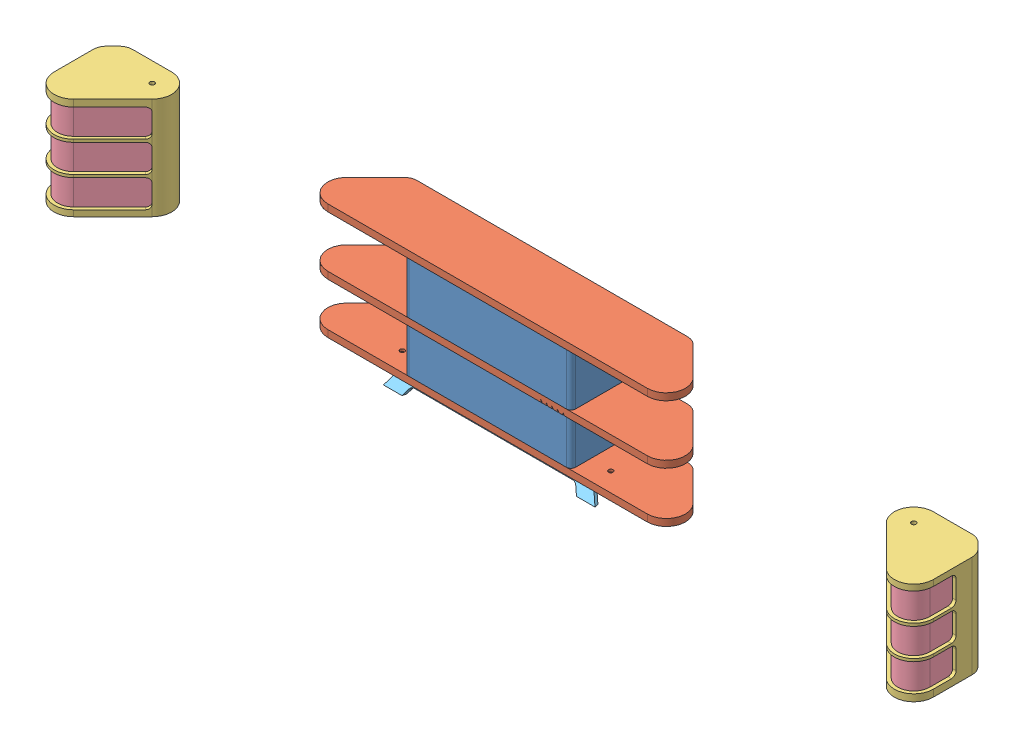
SolidWorks assembly Speakers removed, configuration Default. Lengths in mm.
Overall size (5109.88 725.08 617.93).
10 component instances, 5 part files, 25 mates.
Components (placement in the parent):
- Middle-1: Middle [Default] at (409.9999 227.4076 645.5134) size (914.4 558.8 355.6)
- top bottom-1: top bottom [Default] at (352.252 227.4076 660.7734) x (-1 0 0) z (0 0 1) size (1960.6 38.1 355.6)
- top bottom-2: top bottom [Default] at (467.7478 786.2076 660.7734) size (1960.6 38.1 355.6)
- speaker-1: speaker [Default] at (-1746.1738 107.9388 721.7134) x (0.707107 0 -0.707107) z (0.707107 0 0.707107) size (518.28 558.8 355.6)
- insert-1: insert [Default] at (-1800.5019 139.6888 633.9363) x (0.707107 0 -0.707107) z (0.707107 0 0.707107) size (480.18 508 317.5)
- speaker-2: speaker [Default] at (2566.1737 666.7388 721.7134) x (-0.707107 0 -0.707107) z (-0.707107 0 0.707107) size (518.28 558.8 355.6)
- insert-2: insert [Default] at (2653.9508 139.6888 667.3853) x (0.707107 0 0.707107) z (-0.707107 0 0.707107) size (480.18 508 317.5)
- top bottom-3: top bottom [Default] at (467.7478 466.011 660.7734) size (1960.6 38.1 355.6)
- feet-1: feet [Default] at (409.9999 198.1951 531.0014) x (1 0 0) z (0 -0.457029 0.889452) size (1159.95 101.27 19.05)
- feet-2: feet [Default] at (409.9999 198.1951 767.9726) x (-1 0 0) z (0 -0.457029 -0.889452) size (1159.95 101.27 19.05)
Mates (geometry in assembly coordinates):
- Coincident1: coincident anti-aligned: plane of Middle-1 through (409.9999 786.2076 645.5134) normal (0 1 0); plane of top bottom-2 through (-331.4645 786.2076 541.3734) normal (0 -1 0)
- Coincident2: coincident aligned: plane of Middle-1 through (-47.2001 786.2076 823.3134) normal (0 0 1); plane of top bottom-2 through (1280.027 824.3076 823.3134) normal (0 0 1)
- Coincident3: coincident aligned: plane of Middle-1 through (-47.2001 786.2076 823.3134) normal (0 0 1); plane of top bottom-1 through (-460.0272 189.3076 823.3134) normal (0 0 1)
- Coincident4: coincident anti-aligned: plane of Middle-1 through (409.9999 227.4076 645.5134) normal (0 -1 0); plane of top bottom-1 through (1151.4644 227.4076 541.3734) normal (0 1 0)
- Coincident5: coincident aligned: plane of top bottom-1 through (1355.4612 189.3076 641.1993) normal (0.707107 0 -0.707107); plane of top bottom-2 through (1359.7972 824.3076 645.5353) normal (0.707107 0 -0.707107)
- Width1: width anti-aligned: plane of top bottom-2 through (1359.7972 824.3076 645.5353) normal (0.707107 0 -0.707107); plane of top bottom-2 through (-535.4613 824.3076 641.1993) normal (-0.707107 0 -0.707107); plane of Middle-1 through (-47.2001 786.2076 823.3134) normal (-1 0 0); plane of Middle-1 through (867.1999 786.2076 823.3134) normal (1 0 0)
- Coincident7: coincident anti-aligned: plane of speaker-1 through (-765.667 107.9388 438.524) normal (-0.707107 0 -0.707107); plane of insert-1 through (-1179.114 647.6888 851.9709) normal (0.707107 0 0.707107)
- Coincident8: coincident anti-aligned: plane of speaker-1 through (-1093.7577 647.6888 721.7134) normal (0 -1 0); plane of insert-1 through (-1239.247 647.6888 543.9134) normal (0 1 0)
- Coincident9: coincident anti-aligned: plane of speaker-1 through (-1328.7077 666.7388 467.7134) normal (1 0 0); plane of insert-1 through (-1328.7077 647.6888 576.2242) normal (-1 0 0)
- Coincident11: coincident anti-aligned: plane of speaker-2 through (2238.083 666.7388 438.524) normal (0.707107 0 -0.707107); plane of insert-2 through (2435.9162 647.6888 636.3572) normal (-0.707107 0 0.707107)
- Coincident12: coincident anti-aligned: plane of speaker-2 through (2566.1737 647.6888 721.7134) normal (0 -1 0); plane of insert-2 through (2743.9737 647.6888 576.2242) normal (0 1 0)
- Coincident13: coincident anti-aligned: plane of speaker-2 through (2801.1237 107.9388 467.7134) normal (-1 0 0); plane of insert-2 through (2801.1237 647.6888 790.0072) normal (1 0 0)
- Coincident14: coincident aligned: plane of top bottom-2 through (1280.027 824.3076 823.3134) normal (0 0 1); plane of top bottom-3 through (1280.027 504.111 823.3134) normal (0 0 1)
- Coincident15: coincident aligned: plane of top bottom-2 through (-535.4613 824.3076 641.1993) normal (-0.707107 0 -0.707107); plane of top bottom-3 through (-535.4613 504.111 641.1993) normal (-0.707107 0 -0.707107)
- Coincident17: coincident anti-aligned: plane of top bottom-1 through (1151.4644 189.3076 541.3734) normal (0 -1 0); plane of feet-2 through (989.9752 189.3076 814.3493) normal (0 1 0)
- Coincident18: coincident anti-aligned: plane of top bottom-1 through (1151.4644 189.3076 541.3734) normal (0 -1 0); plane of feet-1 through (-169.9754 189.3076 484.6248) normal (0 1 0)
- Parallel1: parallel: plane of top bottom-1 through (-460.0272 189.3076 823.3134) normal (0 0 1); line of feet-2 through (938.1929 189.3076 772.5393) axis (-1 0 0)
- Width2: width anti-aligned: plane of top bottom-1 through (1355.4612 189.3076 641.1993) normal (0.707107 0 -0.707107); plane of top bottom-1 through (-539.7974 189.3076 645.5353) normal (-0.707107 0 -0.707107); plane of feet-1 through (-120.1337 177.9796 542.0317) normal (-0.871403 0.436336 0.224204); plane of feet-1 through (940.1336 177.9796 542.0317) normal (0.871403 0.436336 0.224204)
- Width3: width aligned: plane of top bottom-1 through (-539.7974 189.3076 645.5353) normal (-0.707107 0 -0.707107); plane of top bottom-1 through (1355.4612 189.3076 641.1993) normal (0.707107 0 -0.707107); plane of feet-2 through (-120.1337 177.9796 756.9423) normal (-0.871403 0.436336 -0.224204); plane of feet-2 through (940.1336 177.9796 756.9423) normal (0.871403 0.436336 -0.224204)
- Coincident22: coincident aligned: plane of speaker-2 through (2566.1737 107.9388 721.7134) normal (0 -1 0); plane of feet-2 through (989.9752 107.9388 814.3493) normal (0 -1 0)
- Coincident23: coincident aligned: plane of speaker-1 through (-1093.7577 107.9388 721.7134) normal (0 -1 0); plane of feet-2 through (989.9752 107.9388 814.3493) normal (0 -1 0)
- Coincident24: coincident aligned: plane of Middle-1 through (-47.2001 786.2076 467.7134) normal (0 0 -1); plane of speaker-1 through (-839.7577 666.7388 467.7134) normal (0 0 -1)
- Coincident25: coincident aligned: plane of Middle-1 through (-47.2001 786.2076 467.7134) normal (0 0 -1); plane of speaker-2 through (2312.1737 107.9388 467.7134) normal (0 0 -1)
- Distance2: distance = 1524 mm anti-aligned: plane of Middle-1 through (867.1999 786.2076 823.3134) normal (1 0 0); cylinder of speaker-2 through (2497.8799 666.7388 574.3934) axis (0 1 0) radius 106.68
- Distance3: distance = 1524 mm anti-aligned: plane of Middle-1 through (-47.2001 786.2076 823.3134) normal (-1 0 0); cylinder of speaker-1 through (-1677.8801 107.9388 574.3934) axis (0 -1 0) radius 106.68
